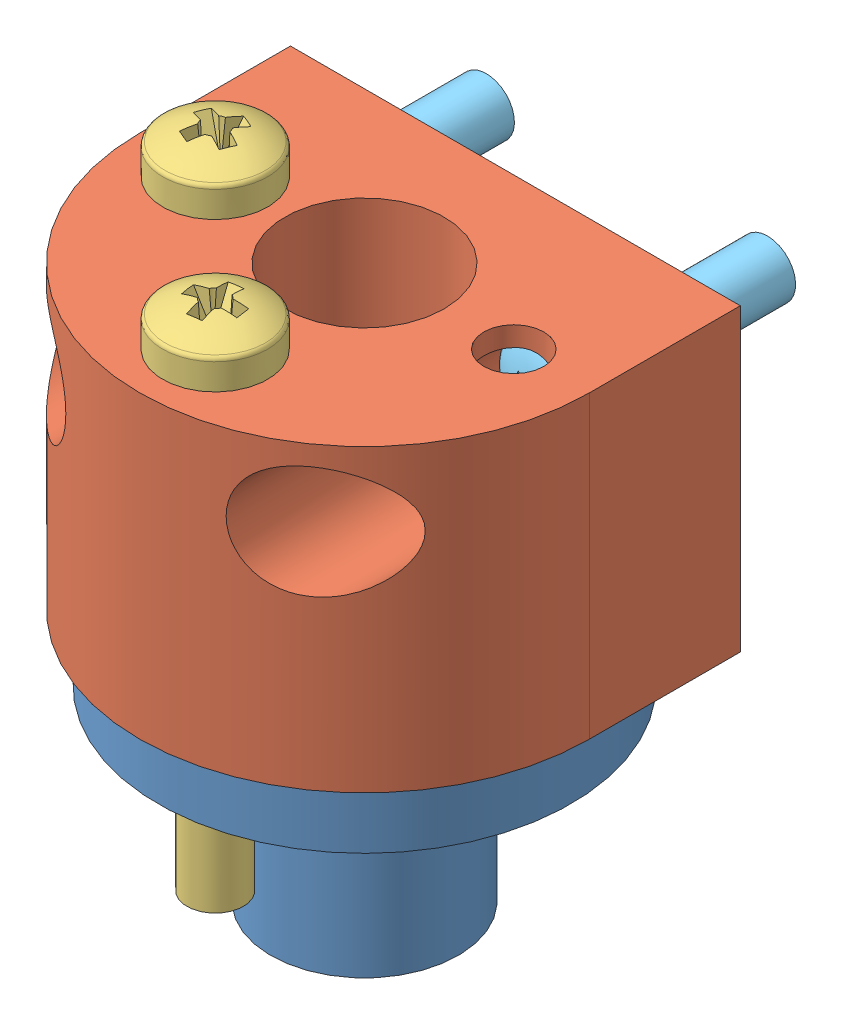
SolidWorks assembly Treaded Rod Female assembly, configuration Default. Lengths in mm.
Overall size (31.11 31.85 31.11).
9 component instances, 5 part files, 19 mates.
Components (placement in the parent):
- Treaded Rod Female Special Nut-1: Treaded Rod Female Special Nut [Default] at (164.5411 -19.5 -148.1318) x (-0.710239 0 -0.703961) z (0 1 0) size (22 22 13.5)
- Z nut atachment to X Bridge3-1: Z nut atachment to X Bridge3 [Valor predeterminado] at (-93.9772 -10 -294.7159) x (1 0 0) z (0 1 0) size (24 20.05 16)
- pan head cross recess screw_iso1-4: pan head cross recess screw_iso1 [ISO 7045 - M3 x 25 - Z --- 25N] at (1.7046 2.4 8.05) x (0 -1 0) z (0.391235 0 -0.920291) size (27.35 5.6 5.6)
- pan head cross recess screw_iso1-5: pan head cross recess screw_iso1 [ISO 7045 - M3 x 25 - Z --- 25N] at (9.6694 2.4 16.0147) x (0 -1 0) z (-0.137779 0 -0.990463) size (27.35 5.6 5.6)
- hex thin nut chamfered gradeab_iso1-1: hex thin nut chamfered gradeab_iso1 [Hexagon Thin Nut ISO - 4035 - M3 - N] at (17.6341 -16 8.05) x (-0.984423 0 -0.175818) z (0 -1 0) size (5.5 6.35 1.8)
- hex thin nut chamfered gradeab_iso1-2: hex thin nut chamfered gradeab_iso1 [Hexagon Thin Nut ISO - 4035 - M3 - N] at (9.6694 -16 0.0853) x (0.986386 0 0.164445) z (0 -1 0) size (5.5 6.35 1.8)
- hex thin nut chamfered gradeab_iso1-3: hex thin nut chamfered gradeab_iso1 [Hexagon Thin Nut ISO - 4035 - M3 - N] at (1.7046 -17.8 8.05) x (0.920291 0 0.391235) z (0 -1 0) size (5.5 6.35 1.8)
- pan cross head_am1-1: pan cross head_am1 [B18.6.7M - M3 x 0.5 x 10 Type I Cross Recessed PHMS --10N] at (1.6194 -4.0507 5.9) x (0 0 -1) z (-0.613187 -0.789937 0) size (12.37 5.6 5.6)
- pan cross head_am1-2: pan cross head_am1 [B18.6.7M - M3 x 0.5 x 10 Type I Cross Recessed PHMS --10N] at (16.6194 -4.0507 5.9) x (0 0 -1) z (0.925719 -0.378212 0) size (12.37 5.6 5.6)
Mates (geometry in assembly coordinates):
- Concentric401223: concentric anti-aligned: cylinder of Treaded Rod Female Special Nut-1 through (9.6694 -29.5 8.05) axis (0 1 0) radius 5; cylinder of Z nut atachment to X Bridge3-1 through (9.6694 16 8.05) axis (0 -1 0) radius 5.25
- Concentric401224: concentric anti-aligned: cylinder of Treaded Rod Female Special Nut-1 through (1.7046 -16 8.05) axis (0 -1 0) radius 1.45; cylinder of Z nut atachment to X Bridge3-1 through (1.7046 0 8.05) axis (0 1 0) radius 1.6
- Coincident7871428: coincident anti-aligned: plane of Treaded Rod Female Special Nut-1 through (164.5411 -16 -148.1318) normal (0 1 0); plane of Z nut atachment to X Bridge3-1 through (9.6694 -16 8.05) normal (0 -1 0)
- Concentric401225: concentric aligned: cylinder of Z nut atachment to X Bridge3-1 through (1.7046 0 8.05) axis (0 1 0) radius 1.6; cylinder of pan head cross recess screw_iso-4 through (1.7046 27.8 8.05) axis (0 1 0) radius 1.5
- Coincident7871429: coincident anti-aligned: plane of Z nut atachment to X Bridge3-1 through (9.6694 0 8.05) normal (0 1 0); plane of pan head cross recess screw_iso-4 through (0.3242 0 7.4631) normal (0 -1 0)
- Concentric401227: concentric aligned: cylinder of Z nut atachment to X Bridge3-1 through (9.6694 0 16.0147) axis (0 1 0) radius 1.6; cylinder of pan head cross recess screw_iso-5 through (9.6694 27.8 16.0147) axis (0 1 0) radius 1.5
- Concentric401228: concentric aligned: cylinder of Z nut atachment to X Bridge3-1 through (1.6194 -4.0507 20) axis (0 0 1) radius 1.6; cylinder of pan cross head_am-1 through (1.6194 -4.0507 31.3) axis (0 0 1) radius 1.5
- Concentric401229: concentric aligned: cylinder of Z nut atachment to X Bridge3-1 through (16.6194 -4.0507 20) axis (0 0 1) radius 1.6; cylinder of pan cross head_am-2 through (16.6194 -4.0507 31.3) axis (0 0 1) radius 1.5
- Concentric401230: concentric anti-aligned: cylinder of pan head cross recess screw_iso-4 through (1.7046 27.8 8.05) axis (0 1 0) radius 1.5; cylinder of hex thin nut chamfered gradeab_iso-3 through (1.7046 -16 8.05) axis (0 -1 0) radius 1.25
- Concentric401231: concentric aligned: cylinder of Treaded Rod Female Special Nut-1 through (9.6694 -16 0.0853) axis (0 -1 0) radius 1.45; cylinder of hex thin nut chamfered gradeab_iso-2 through (9.6694 -14.2 0.0853) axis (0 -1 0) radius 1.25
- Concentric401232: concentric aligned: cylinder of Treaded Rod Female Special Nut-1 through (17.6341 -16 8.05) axis (0 -1 0) radius 1.45; cylinder of hex thin nut chamfered gradeab_iso-1 through (17.6341 -14.2 8.05) axis (0 -1 0) radius 1.25
- Coincident7871430: coincident anti-aligned: plane of Treaded Rod Female Special Nut-1 through (164.5411 -16 -148.1318) normal (0 1 0); plane of hex thin nut chamfered gradeab_iso-1 through (18.1924 -16 4.924) normal (0 -1 0)
- Coincident7871431: coincident aligned: plane of Treaded Rod Female Special Nut-1 through (164.5411 -16 -148.1318) normal (0 1 0); plane of hex thin nut chamfered gradeab_iso-3 through (0.4623 -16 10.9723) normal (0 1 0)
- Coincident7871432: coincident anti-aligned: plane of Treaded Rod Female Special Nut-1 through (164.5411 -16 -148.1318) normal (0 1 0); plane of hex thin nut chamfered gradeab_iso-2 through (9.1472 -16 3.2175) normal (0 -1 0)
- Coincident7871433: coincident anti-aligned: plane of Z nut atachment to X Bridge3-1 through (9.6694 0 8.05) normal (0 1 0); plane of pan head cross recess screw_iso-5 through (8.1837 0 16.2214) normal (0 -1 0)
- Coincident7871435: coincident anti-aligned: plane of Z nut atachment to X Bridge3-1 through (18.2194 -4.0507 3.5) normal (0 0 1); plane of pan cross head_am-2 through (17.1867 -2.6621 3.5) normal (0 0 -1)
- Coincident7871436: coincident anti-aligned: plane of Z nut atachment to X Bridge3-1 through (3.2194 -4.0507 3.5) normal (0 0 1); plane of pan cross head_am-1 through (2.8043 -4.9704 3.5) normal (0 0 -1)
- Coincident7871437: coincident anti-aligned: plane of Z nut atachment to X Bridge3-1 through (-93.9772 -10 0) normal (0 0 -1); plane of assembly through (0 0 0) normal (0 0 1)
- Coincident7871438: coincident aligned: plane of Z nut atachment to X Bridge3-1 through (9.6694 0 8.05) normal (0 1 0); plane of assembly through (0 0 0) normal (0 1 0)
